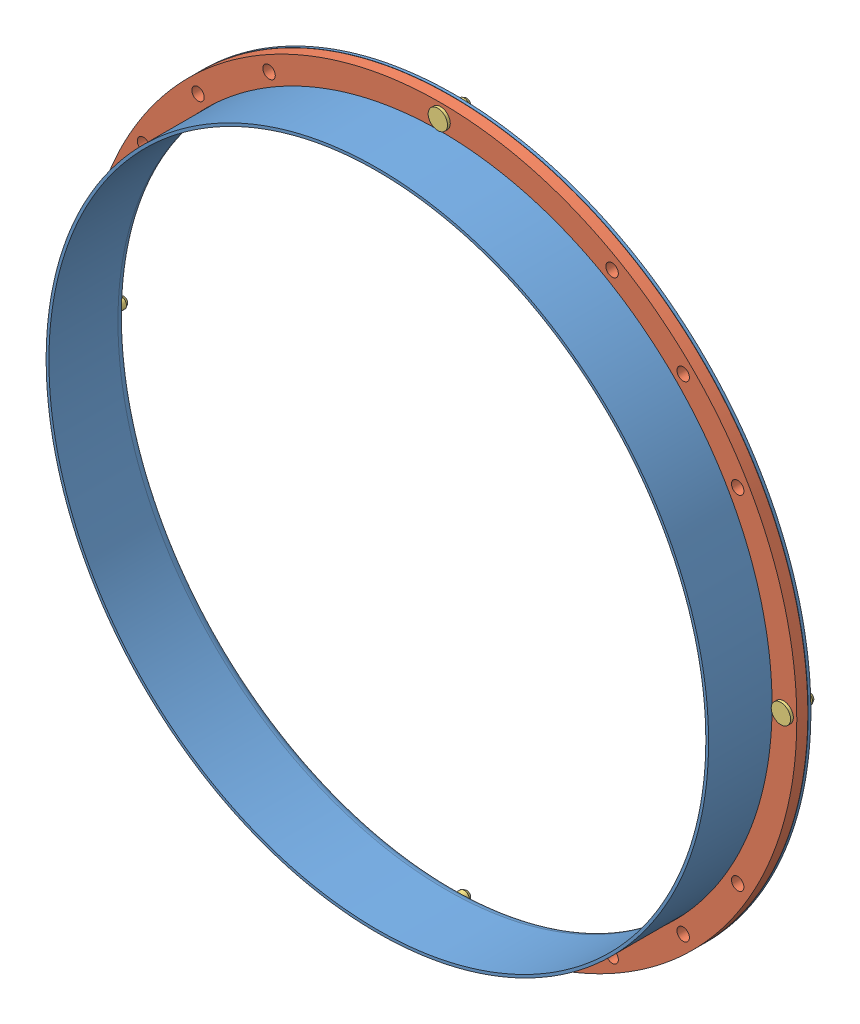
SolidWorks assembly MSC_Small_Flange_asm, configuration Default. Lengths in mm.
Overall size (258 258 32.4).
6 component instances, 3 part files, 9 mates.
Components (placement in the parent):
- MSC_Small_Flange_Base-1: MSC_Small_Flange_Base [Default] at origin size (258 258 28)
- MSC_Small_Flange_Backer-1: MSC_Small_Flange_Backer [Default] at (0 0 1.1) size (258 258 4.11)
- IDS Flange Alignment Pin-1: IDS Flange Alignment Pin [MSC short] at (0 124.25 5.1) x (0 0 -1) z (1 0 0) size (10.5 7 7)
- IDS Flange Alignment Pin-2: IDS Flange Alignment Pin [MSC short] at (-124.25 0 5.1) x (0 0 -1) z (0 1 0) size (10.5 7 7)
- IDS Flange Alignment Pin-3: IDS Flange Alignment Pin [MSC short] at (0 -124.25 5.1) x (0 0 -1) z (-1 0 0) size (10.5 7 7)
- IDS Flange Alignment Pin-4: IDS Flange Alignment Pin [MSC short] at (124.25 0 5.1) x (0 0 -1) z (0 -1 0) size (10.5 7 7)
Mates (geometry in assembly coordinates):
- Distance1: distance = 0.1 mm anti-aligned: plane of MSC_Small_Flange_Base-1 through (0 121.95 1) normal (0 0 1); plane of MSC_Small_Flange_Backer-1 through (0 129 1.1) normal (0 0 -1)
- Coincident1: coincident aligned: plane of MSC_Small_Flange_Base-1 through (0 0 0) normal (0 0 1); plane of assembly through (0 0 0) normal (0 0 1)
- Coincident2: coincident aligned: plane of MSC_Small_Flange_Base-1 through (0 0 0) normal (0 1 0); plane of assembly through (0 0 0) normal (0 1 0)
- Coincident3: coincident aligned: plane of MSC_Small_Flange_Base-1 through (0 0 0) normal (1 0 0); plane of assembly through (0 0 0) normal (1 0 0)
- Coincident4: coincident aligned: plane of MSC_Small_Flange_Backer-1 through (0 0 1.1) normal (0 1 0); plane of assembly through (0 0 0) normal (0 1 0)
- Coincident5: coincident aligned: plane of MSC_Small_Flange_Backer-1 through (0 0 1.1) normal (1 0 0); plane of assembly through (0 0 0) normal (1 0 0)
- Concentric1: concentric aligned: cylinder of MSC_Small_Flange_Backer-1 through (0 124.25 5.1) axis (0 0 1) radius 2; cylinder of IDS Flange Alignment Pin-1 through (0 124.25 35.2671) axis (0 0 1) radius 2.0025
- Coincident6: coincident anti-aligned: plane of MSC_Small_Flange_Backer-1 through (0 129 5.1) normal (0 0 1); plane of IDS Flange Alignment Pin-1 through (0 126.2525 5.1) normal (0 0 -1)
- Parallel1: parallel aligned: plane of IDS Flange Alignment Pin-1; plane of assembly through (0 0 0) normal (0 1 0)
